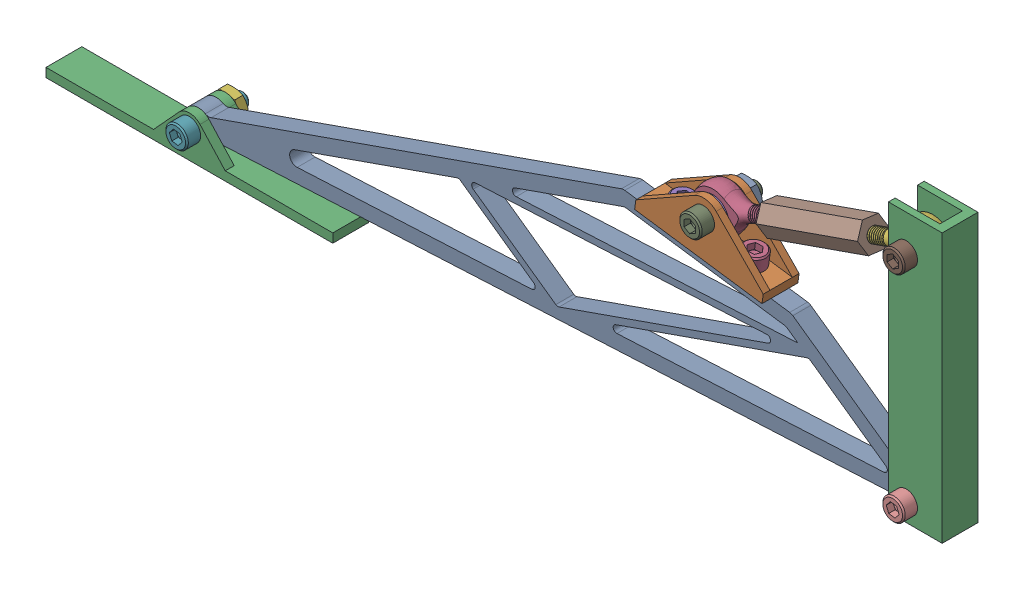
SolidWorks assembly Corner Assembly, configuration Default. Lengths in mm.
Overall size (317.5 111.13 23.88).
17 component instances, 11 part files, 0 mates.
Components (placement in the parent):
- Leg-1: Leg [Default] at (-81.9604 100.7587 355.4692) size (264.16 60.38 6.35)
- Part2^Corner Assembly-1: Part2^Corner Assembly [Default] at (-188.4761 192.3861 355.4692) x (0.990189 -0.139734 0) z (0.139734 0.990189 0) size (45.57 12.7 19.05)
- Part3^Corner Assembly-1: Part3^Corner Assembly [Default] at (0 0 358.6442) size (19.05 95.25 12.7)
- 60645K111_STEEL BALL JOINT ROD END_60645K111-1: 60645K111_STEEL BALL JOINT ROD END_60645K111 [Default] at (112.1046 168.6814 358.6442) x (-0.33035 0.943858 0) z (0 0 1) size (15.88 39.69 15.88)
- 60645K112_STEEL BALL JOINT ROD END_60645K112-1: 60645K112_STEEL BALL JOINT ROD END_60645K112 [Default] at (160.0526 185.4632 358.6442) x (0.33035 -0.943858 0) z (0 0 1) size (15.88 39.69 15.88)
- Turnbuckle-1: Turnbuckle [Default] at (154.0591 183.3655 358.6442) x (-0.268128 0.766079 -0.584149) z (-0.943858 -0.33035 0) size (11 9.53 38.1)
- socket head cap screw_ai_HX-SHCS 0.19-32x0.75x0.75-N-1: socket head cap screw_ai_HX-SHCS 0.19-32x0.75x0.75-N [Default] at (100.1176 164.486 369.8202) x (0 0 -1) z (1 0 0) size (23.88 7.94 7.94)
- socket head cap screw_ai_HX-SHCS 0.19-32x0.75x0.75-N-2: socket head cap screw_ai_HX-SHCS 0.19-32x0.75x0.75-N [Default] at (172.0396 113.4587 369.8202) x (0 0 -1) z (-0.923728 -0.383049 0) size (23.88 7.94 7.94)
- socket head cap screw_ai_HX-SHCS 0.19-32x0.75x0.75-N-3: socket head cap screw_ai_HX-SHCS 0.19-32x0.75x0.75-N [Default] at (172.0396 189.6587 369.8202) x (0 0 -1) z (1 0 0) size (23.88 7.94 7.94)
- machine screw nut hex_ai_MSHXNUT 0.164-36-S-N-1: machine screw nut hex_ai_MSHXNUT 0.164-36-S-N [Default] at (172.0396 189.6587 348.9922) x (0.923728 0.383049 0) z (0 0 -1) size (8.74 10.09 3.3)
- machine screw nut hex_ai_MSHXNUT 0.190-32-S-N-1: machine screw nut hex_ai_MSHXNUT 0.190-32-S-N [Default] at (100.1176 164.486 348.9922) x (0.923728 0.383049 0) z (0 0 -1) size (9.53 11 3.3)
- machine screw nut hex_ai_MSHXNUT 0.190-32-S-N-2: machine screw nut hex_ai_MSHXNUT 0.190-32-S-N [Default] at (172.0396 113.4587 348.9922) x (0.923728 0.383049 0) z (0 0 -1) size (9.53 11 3.3)
- Part5^Corner Assembly-1: Part5^Corner Assembly [Default] at (-81.9604 100.7587 355.4692) x (-1 0 0) z (0 0 -1) size (101.6 14.61 12.7)
- socket head cap screw_ai_HX-SHCS 0.19-32x0.375x0.375-N-1: socket head cap screw_ai_HX-SHCS 0.19-32x0.375x0.375-N [Default] at (112.0364 158.0585 358.6442) x (-0.139734 -0.990189 0) z (0.939632 -0.1326 0.315449) size (14.35 7.94 7.94)
- socket head cap screw_ai_HX-SHCS 0.19-32x0.375x0.375-N-2: socket head cap screw_ai_HX-SHCS 0.19-32x0.375x0.375-N [Default] at (86.8856 161.6077 358.6442) x (-0.139734 -0.990189 0) z (0 0 1) size (14.35 7.94 7.94)
- machine screw nut hex_ai_MSHXNUT 0.190-32-S-N-3: machine screw nut hex_ai_MSHXNUT 0.190-32-S-N [Default] at (-81.9604 100.7587 348.9922) x (0.923728 0.383049 0) z (0 0 -1) size (9.53 11 3.3)
- socket head cap screw_ai_HX-SHCS 0.19-32x0.75x0.75-N-4: socket head cap screw_ai_HX-SHCS 0.19-32x0.75x0.75-N [Default] at (-81.9604 100.7587 369.8202) x (0 0 -1) z (-0.923728 -0.383049 0) size (23.88 7.94 7.94)
